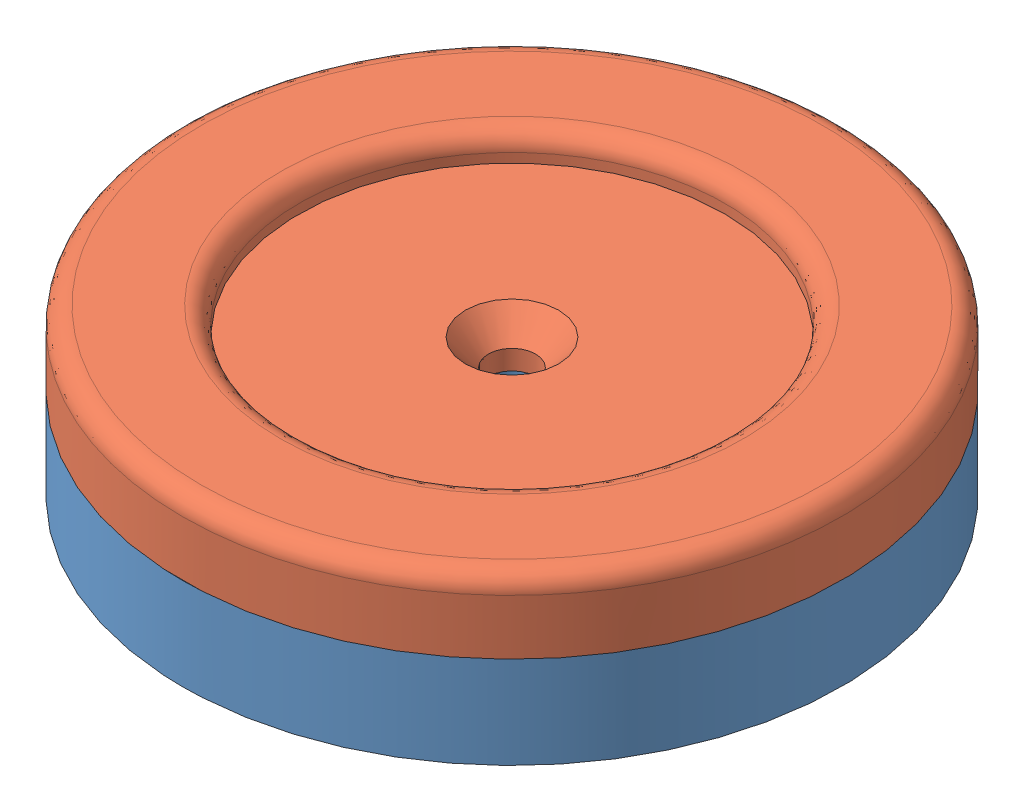
SolidWorks assembly ST_CAP_ASSEMBLY, configuration Default. Lengths in mm.
Overall size (90.93 37.04 90.93).
2 component instances, 2 part files, 2 mates.
Components (placement in the parent):
- ST_Bottom-1: ST_Bottom [Default] at (-61.87 11.0377 25.6518) size (90.93 26.88 90.93)
- ST_Cap-1: ST_Cap [Default] at (-61.87 4.6877 25.6518) size (90.93 29.21 90.93)
Mates (geometry in assembly coordinates):
- Concentric1: concentric: cylinder of ST_Bottom-1 through (-61.87 11.0377 25.6518) axis (0 1 0) radius 3.302; cylinder of ST_Cap-1 through (-61.87 30.0877 25.6518) axis (0 1 0) radius 3.2639
- Coincident1: coincident: plane of ST_Bottom-1 through (-61.87 23.7377 25.6518) normal (0 1 0); plane of ST_Cap-1 through (-61.87 23.7377 25.6518) normal (0 -1 0)
